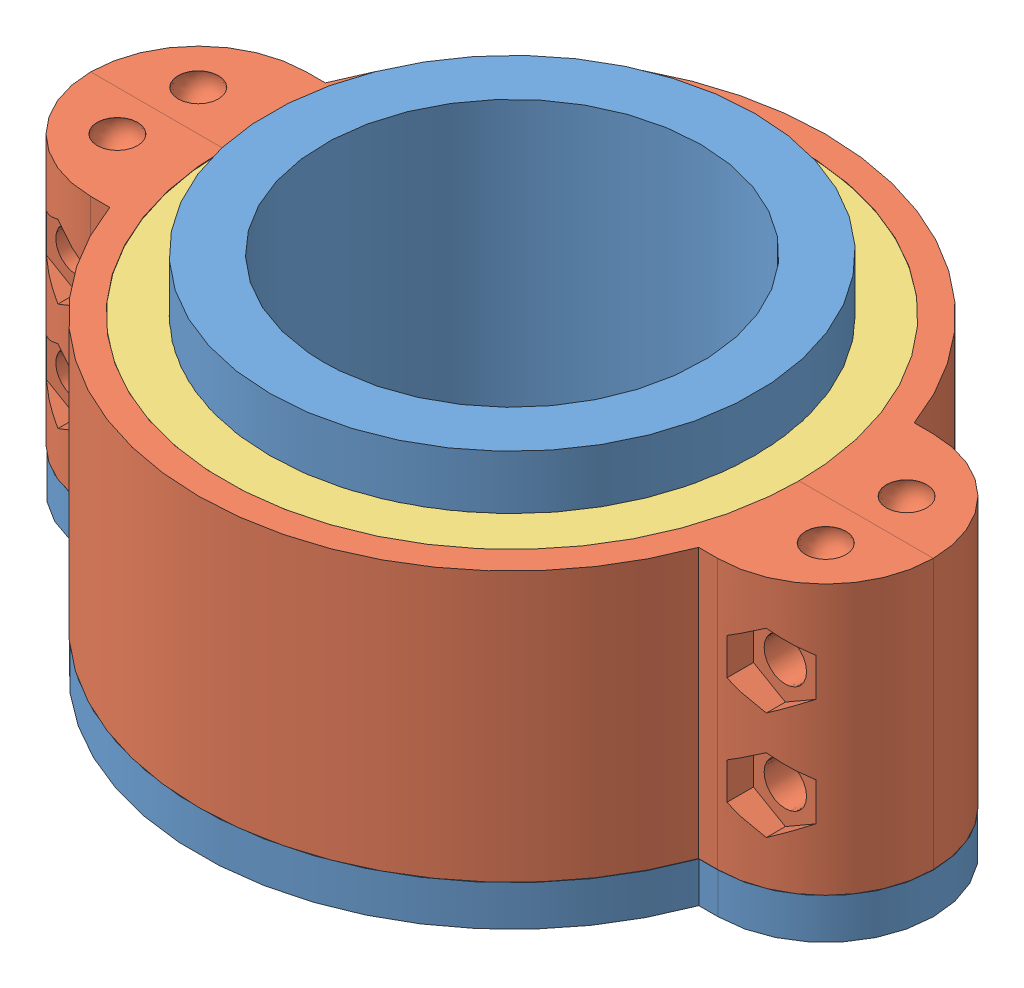
SolidWorks assembly MoldAssembly, configuration Default. Lengths in mm.
Overall size (79.44 48.03 59.1).
4 component instances, 3 part files, 5 mates.
Components (placement in the parent):
- MoldBase-1: MoldBase [Default] at (-42.6592 51.5171 92.2726) size (79.42 48.03 59.1)
- MoldSideA-1: MoldSideA [Default] at (-42.6799 64.2425 92.2726) size (79.42 27.71 29.55)
- MoldSideA-2: MoldSideA [Default] at (-42.6799 64.2425 92.2726) x (-1 0 0) z (0 0 -1) size (79.42 27.71 29.55)
- ceramic spacer-1: ceramic spacer [Default] at (-42.6592 64.2171 92.2726) x (0.999996 0 -0.002701) z (0.002701 0 0.999996) size (54.1 25.4 54.1)
Mates (geometry in assembly coordinates):
- Coincident4: coincident anti-aligned: circle of MoldBase-1; circle of MoldSideA-1
- Coincident8: coincident anti-aligned: circle of MoldBase-1; circle of MoldSideA-2
- Concentric6: concentric aligned: circle of MoldBase-1; circle of ceramic spacer-1
- Coincident9: coincident anti-aligned: plane of MoldBase-1 through (-42.6592 51.5171 92.2726) normal (0 1 0); plane of ceramic spacer-1 through (-42.6592 51.5171 92.2726) normal (0 -1 0)
- Coincident10: coincident anti-aligned: plane of MoldSideA-1 through (-13.1302 51.5425 92.2726) normal (0 0 -1); plane of MoldSideA-2 through (-15.6289 51.5425 92.2726) normal (0 0 1)
